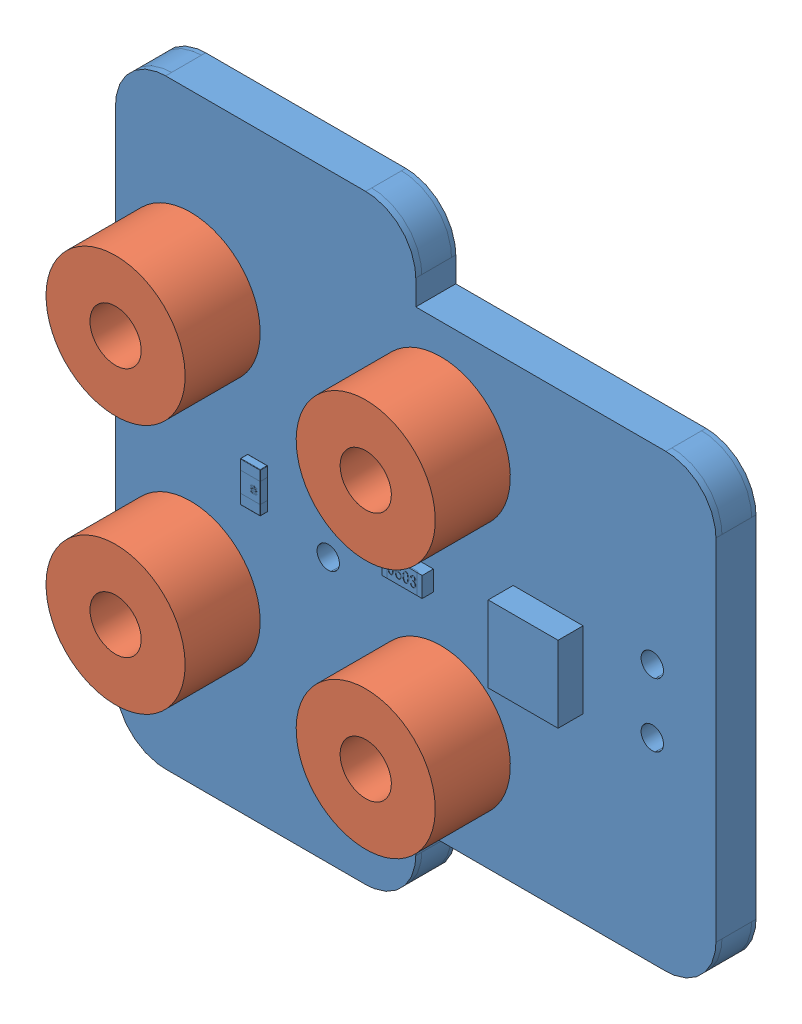
SolidWorks assembly Magnetic_PCB_with_SDM-nut_with_thickness, configuration 默认. Lengths in mm.
Overall size (24.64 24.01 5.9).
5 component instances, 2 part files, 8 mates.
Components (placement in the parent):
- Magnetic_PCB_with_SDM-nut_with_thickness-1: Magnetic_PCB_with_SDM-nut_with_thickness [默认] at (-126.959 42.921 -25.2644) size (24.01 24.01 4)
- 贴片螺母SMTSO-M2.5-3ET-1: 贴片螺母SMTSO-M2.5-3ET [默认] at (-140.6253 49.2542 0.9) x (-0.923728 -0.383049 0) z (0.383049 -0.923728 0) size (5.56 4.53 5.56)
- 贴片螺母SMTSO-M2.5-3ET-2: 贴片螺母SMTSO-M2.5-3ET [默认] at (-130.6253 49.2542 0.9) x (-0.923728 -0.383049 0) z (0.383049 -0.923728 0) size (5.56 4.53 5.56)
- 贴片螺母SMTSO-M2.5-3ET-3: 贴片螺母SMTSO-M2.5-3ET [默认] at (-140.6253 39.2542 0.9) x (-0.923728 -0.383049 0) z (0.383049 -0.923728 0) size (5.56 4.53 5.56)
- 贴片螺母SMTSO-M2.5-3ET-4: 贴片螺母SMTSO-M2.5-3ET [默认] at (-130.6253 39.2542 0.9) x (-0.923728 -0.383049 0) z (0.383049 -0.923728 0) size (5.56 4.53 5.56)
Mates (geometry in assembly coordinates):
- 同心1: concentric aligned: cylinder of Magnetic_PCB_with_SDM-nut_with_thickness-1 through (-140.6253 49.2542 -0.7) axis (0 0 -1) radius 2.11; cylinder of 贴片螺母SMTSO-M2.5-3ET-1 through (-140.6253 49.2542 -0.63) axis (0 0 -1) radius 1.025
- 同心2: concentric aligned: cylinder of Magnetic_PCB_with_SDM-nut_with_thickness-1 through (-130.6253 49.2542 -0.7) axis (0 0 -1) radius 2.11; cylinder of 贴片螺母SMTSO-M2.5-3ET-2 through (-130.6253 49.2542 -0.63) axis (0 0 -1) radius 1.025
- 同心3: concentric aligned: cylinder of Magnetic_PCB_with_SDM-nut_with_thickness-1 through (-140.6253 39.2542 -0.7) axis (0 0 -1) radius 2.11; cylinder of 贴片螺母SMTSO-M2.5-3ET-3 through (-140.6253 39.2542 -0.63) axis (0 0 -1) radius 1.025
- 同心4: concentric aligned: cylinder of Magnetic_PCB_with_SDM-nut_with_thickness-1 through (-130.6253 39.2542 -0.7) axis (0 0 -1) radius 2.11; cylinder of 贴片螺母SMTSO-M2.5-3ET-4 through (-130.6253 39.2542 -0.63) axis (0 0 -1) radius 1.025
- 重合1: coincident anti-aligned: plane of Magnetic_PCB_with_SDM-nut_with_thickness-1 through (-143.6253 34.2542 0.9) normal (0 0 1); circle of 贴片螺母SMTSO-M2.5-3ET-1
- 重合2: coincident aligned: plane of 贴片螺母SMTSO-M2.5-3ET-1 through (-140.6253 49.2542 3.9) normal (0 0 1); plane of 贴片螺母SMTSO-M2.5-3ET-2 through (-130.6253 49.2542 3.9) normal (0 0 1)
- 重合3: coincident aligned: plane of 贴片螺母SMTSO-M2.5-3ET-1 through (-140.6253 49.2542 3.9) normal (0 0 1); plane of 贴片螺母SMTSO-M2.5-3ET-4 through (-130.6253 39.2542 3.9) normal (0 0 1)
- 重合4: coincident aligned: plane of 贴片螺母SMTSO-M2.5-3ET-1 through (-140.6253 49.2542 3.9) normal (0 0 1); plane of 贴片螺母SMTSO-M2.5-3ET-3 through (-140.6253 39.2542 3.9) normal (0 0 1)
